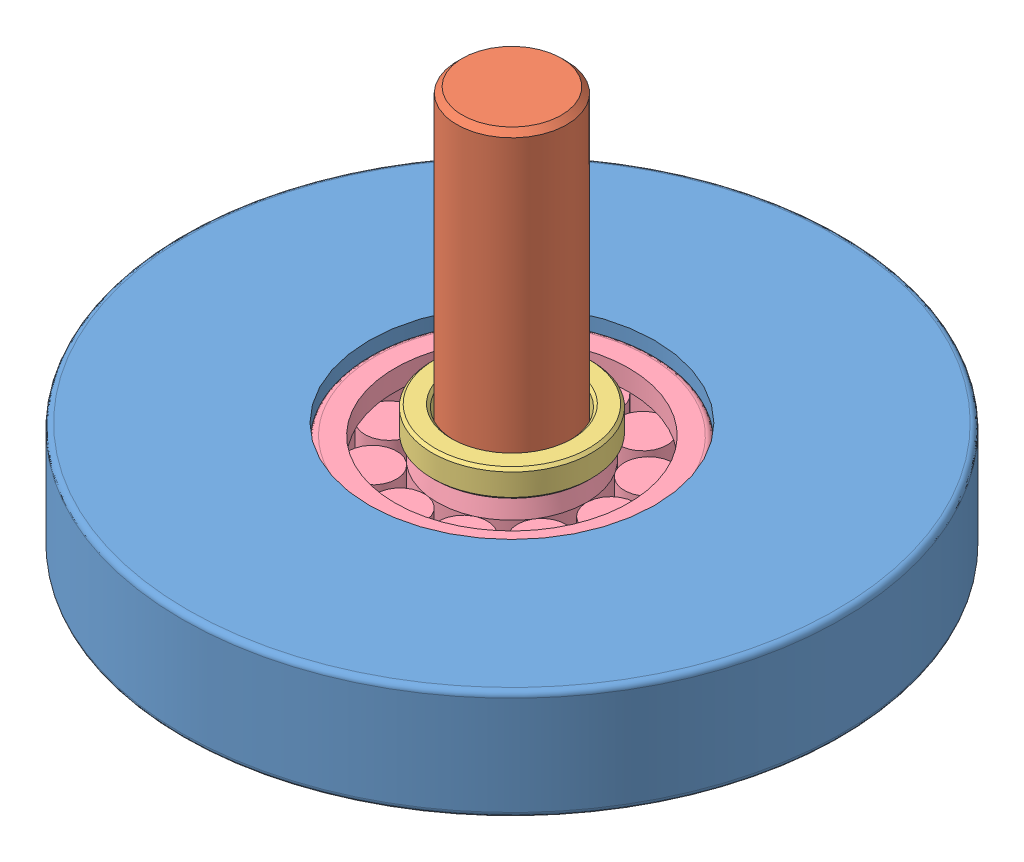
SolidWorks assembly 底层车板前导向轮装配, configuration 默认. Lengths in mm.
Overall size (120 75 120).
4 component instances, 4 part files, 6 mates.
Components (placement in the parent):
- 底层车板前导向轮-1: 底层车板前导向轮 [默认] at (2.7431 4.5383 100) size (120 20 120)
- 底层车板前导向轮轴-1: 底层车板前导向轮轴 [默认] at (2.7431 2.5383 100) x (0.986399 0 0.164367) z (-0.164367 0 0.986399) size (30 75 30)
- 底层车板前导向轮轴套-1: 底层车板前导向轮轴套 [默认] at (2.7431 22.5383 100) size (29 5 29)
- cylindrical roller bearings gb-1: cylindrical roller bearings gb [Rolling bearings NU304E GB 283-94] at (2.7431 15.0383 100) x (0 -1 0) z (0 0 1) size (15 52 52)
Mates (geometry in assembly coordinates):
- 同心1: concentric: cylinder of 底层车板前导向轮轴-1 through (2.7431 77.5383 100) axis (0 -1 0) radius 10; cylinder of cylindrical roller bearings gb-1 through (2.7431 25.1761 100) axis (0 1 0) radius 10
- 重合2: coincident: plane of 底层车板前导向轮轴-1 through (2.7431 7.5383 100) normal (0 1 0); plane of cylindrical roller bearings gb-1 through (12.7431 7.5383 100) normal (0 -1 0)
- 同心2: concentric: cylinder of 底层车板前导向轮-1 through (2.7431 24.5383 100) axis (0 -1 0) radius 26; cylinder of cylindrical roller bearings gb-1 through (2.7431 24.1205 100) axis (0 1 0) radius 26
- 重合3: coincident: plane of 底层车板前导向轮-1 through (2.7431 7.5383 100) normal (0 1 0); plane of cylindrical roller bearings gb-1 through (28.7431 7.5383 100) normal (0 -1 0)
- 同心3: concentric: cylinder of 底层车板前导向轮轴-1 through (2.7431 77.5383 100) axis (0 -1 0) radius 10; cylinder of 底层车板前导向轮轴套-1 through (2.7431 27.5383 100) axis (0 -1 0) radius 10.5
- 重合4: coincident: plane of 底层车板前导向轮轴套-1 through (2.7431 22.5383 100) normal (0 -1 0); plane of cylindrical roller bearings gb-1 through (15.3383 22.5383 100) normal (0 1 0)
